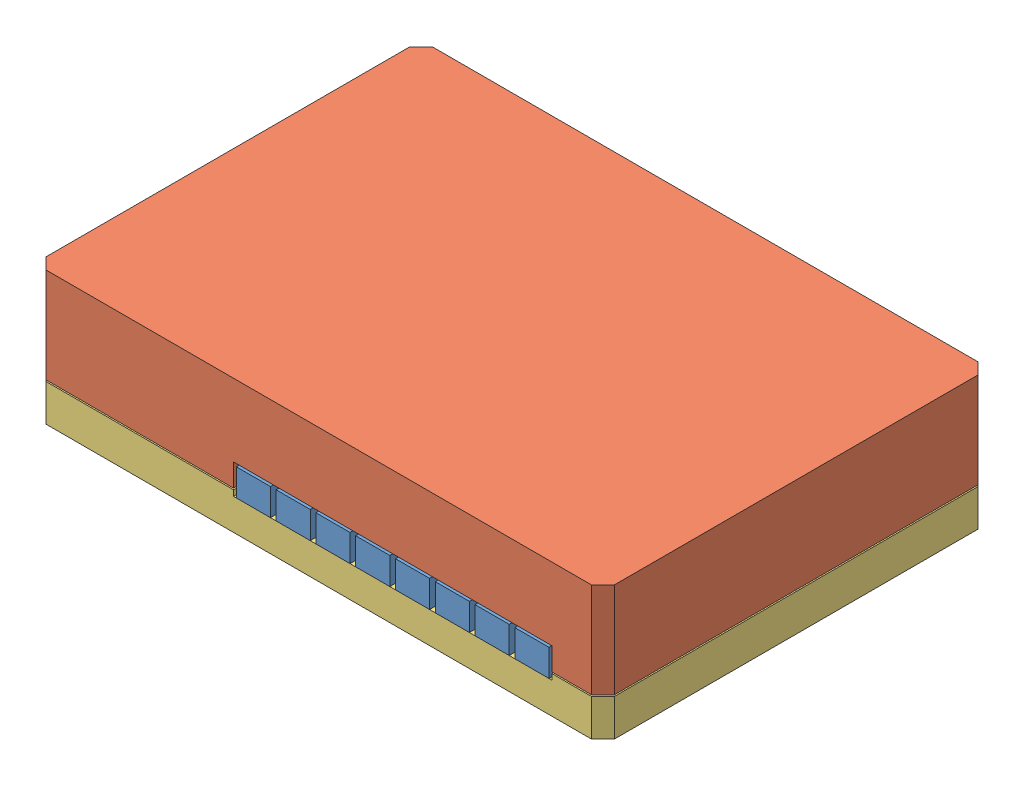
SolidWorks assembly PoppingUnitStackup, configuration Default. Lengths in mm.
Overall size (100 23.5 68).
3 component instances, 3 part files, 6 mates.
Components (placement in the parent):
- PoppingUnitPCB-2: PoppingUnitPCB [Default] at (5.1596 101.55 -25.789) size (97.5 14.2 68)
- PoppingUnitTop-1: PoppingUnitTop [Default] at (7.9472 102.75 -19.6451) size (100 18 68)
- PoppingUnitBottom-2: PoppingUnitBottom [Default] at (50.2484 97.25 -47.4053) size (100 6.5 68)
Mates (geometry in assembly coordinates):
- Concentric2: concentric aligned: cylinder of PoppingUnitBottom-2 through (-49.608 102.75 27.4669) axis (0 -1 0) radius 1.6; cylinder of PoppingUnitPCB-2 through (-49.608 102.75 27.4669) axis (0 -1 0) radius 1.6
- Concentric3: concentric aligned: cylinder of PoppingUnitBottom-2 through (39.392 102.75 27.4669) axis (0 -1 0) radius 1.6; cylinder of PoppingUnitPCB-2 through (39.392 102.75 27.4669) axis (0 -1 0) radius 1.6
- Concentric4: concentric aligned: cylinder of PoppingUnitBottom-2 through (-49.608 102.75 27.4669) axis (0 -1 0) radius 1.6; cylinder of PoppingUnitTop-1 through (-49.608 124.7098 27.4669) axis (0 -1 0) radius 1.4
- Concentric6: concentric aligned: cylinder of PoppingUnitBottom-2 through (39.392 102.75 27.4669) axis (0 -1 0) radius 1.6; cylinder of PoppingUnitTop-1 through (39.392 124.7098 27.4669) axis (0 -1 0) radius 1.4
- Distance1: distance = 0 mm anti-aligned: plane of PoppingUnitBottom-2 through (50.2484 101.55 -47.4053) normal (0 1 0); plane of PoppingUnitPCB-2 through (-49.608 101.55 27.4669) normal (0 -1 0)
- Coincident4: coincident anti-aligned: plane of PoppingUnitPCB-2 through (-49.608 102.75 27.4669) normal (0 1 0); plane of PoppingUnitTop-1 through (7.9472 102.75 -19.6451) normal (0 -1 0)
